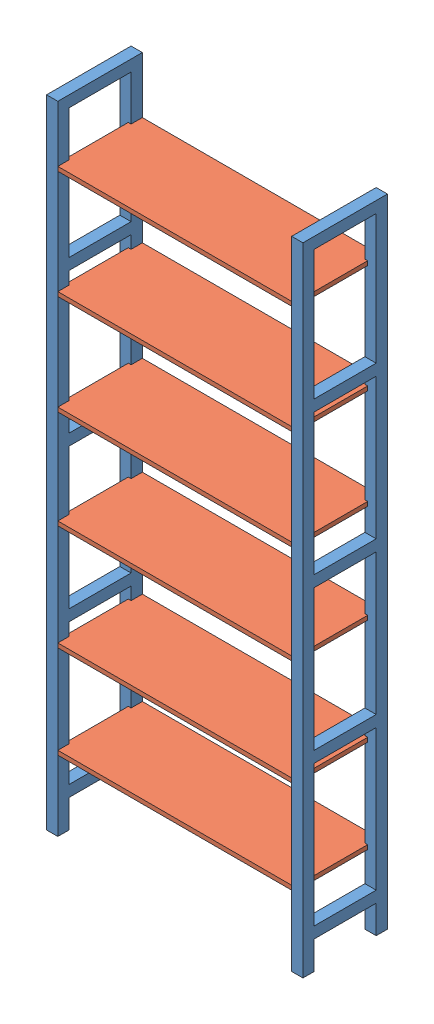
SolidWorks assembly Küchenregal, configuration Standard. Lengths in mm.
Overall size (910 2260 300).
8 component instances, 2 part files, 21 mates.
Components (placement in the parent):
- Seite-30-226-1: Seite-30-226 [Standard] at (-238.8637 -1.8239 2260) size (40 2260 300)
- Seite-30-226-2: Seite-30-226 [Standard] at (631.1363 -1.8239 2260) size (40 2260 300)
- Boden-30-83-1: Boden-30-83 [Standard] at (216.1363 913.1761 2260) size (850 15 300)
- Boden-30-83-2: Boden-30-83 [Standard] at (216.1363 528.1761 2260) size (850 15 300)
- Boden-30-83-3: Boden-30-83 [Standard] at (216.1363 173.1761 2260) size (850 15 300)
- Boden-30-83-4: Boden-30-83 [Standard] at (216.1363 -176.8239 2260) size (850 15 300)
- Boden-30-83-5: Boden-30-83 [Standard] at (216.1363 -551.8239 2260) size (850 15 300)
- Boden-30-83-6: Boden-30-83 [Standard] at (216.1363 -881.8239 2260) size (850 15 300)
Mates (geometry in assembly coordinates):
- Deckungsgleich1: coincident anti-aligned: plane of Seite-30-226-1 through (-198.8637 -1.8239 2260) normal (1 0 0); plane of Boden-30-83-1 through (-198.8637 928.1761 2370) normal (-1 0 0)
- Deckungsgleich2: coincident anti-aligned: plane of Seite-30-226-1 through (-198.8637 -1.8239 2260) normal (1 0 0); plane of Boden-30-83-2 through (-198.8637 543.1761 2370) normal (-1 0 0)
- Deckungsgleich3: coincident anti-aligned: plane of Seite-30-226-1 through (-198.8637 -1.8239 2260) normal (1 0 0); plane of Boden-30-83-3 through (-198.8637 188.1761 2370) normal (-1 0 0)
- Deckungsgleich4: coincident anti-aligned: plane of Seite-30-226-1 through (-198.8637 -1.8239 2260) normal (1 0 0); plane of Boden-30-83-4 through (-198.8637 -161.8239 2370) normal (-1 0 0)
- Deckungsgleich5: coincident: plane of Seite-30-226-1 through (-198.8637 -1.8239 2260) normal (1 0 0); plane of Boden-30-83-6 through (-198.8637 -866.8239 2370) normal (-1 0 0)
- Deckungsgleich6: coincident aligned: plane of Seite-30-226-1 through (-198.8637 1128.1761 2410) normal (0 0 1); plane of Boden-30-83-6 through (-198.8637 -866.8239 2410) normal (0 0 1)
- Deckungsgleich7: coincident: plane of Seite-30-226-1 through (-198.8637 1128.1761 2410) normal (0 0 1); plane of Boden-30-83-5 through (-198.8637 -536.8239 2410) normal (0 0 1)
- Deckungsgleich8: coincident: plane of Seite-30-226-1 through (-198.8637 -1.8239 2260) normal (1 0 0); plane of Boden-30-83-5 through (-198.8637 -536.8239 2370) normal (-1 0 0)
- Deckungsgleich9: coincident aligned: plane of Seite-30-226-1 through (-198.8637 1128.1761 2410) normal (0 0 1); plane of Boden-30-83-4 through (-198.8637 -161.8239 2410) normal (0 0 1)
- Deckungsgleich10: coincident: plane of Seite-30-226-1 through (-198.8637 1128.1761 2410) normal (0 0 1); plane of Boden-30-83-3 through (-198.8637 188.1761 2410) normal (0 0 1)
- Deckungsgleich11: coincident aligned: plane of Seite-30-226-1 through (-198.8637 1128.1761 2410) normal (0 0 1); plane of Boden-30-83-2 through (-198.8637 543.1761 2410) normal (0 0 1)
- Deckungsgleich12: coincident aligned: plane of Seite-30-226-1 through (-198.8637 1128.1761 2410) normal (0 0 1); plane of Boden-30-83-1 through (-198.8637 928.1761 2410) normal (0 0 1)
- Deckungsgleich13: coincident aligned: plane of Seite-30-226-2 through (671.1363 1128.1761 2410) normal (0 0 1); plane of Boden-30-83-1 through (-198.8637 928.1761 2410) normal (0 0 1)
- Deckungsgleich14: coincident anti-aligned: plane of Seite-30-226-2 through (631.1363 -1.8239 2260) normal (-1 0 0); plane of Boden-30-83-1 through (631.1363 928.1761 2410) normal (1 0 0)
- Deckungsgleich15: coincident aligned: plane of Seite-30-226-1 through (-198.8637 1128.1761 2410) normal (0 1 0); plane of Seite-30-226-2 through (671.1363 1128.1761 2410) normal (0 1 0)
- Abstand1: distance = 250 mm aligned: plane of Boden-30-83-6 through (216.1363 -881.8239 2260) normal (0 -1 0); plane of Seite-30-226-2 through (671.1363 -1131.8239 2410) normal (0 -1 0)
- Abstand2: distance = 315 mm: plane of Boden-30-83-5 through (216.1363 -551.8239 2260) normal (0 -1 0); plane of Boden-30-83-6 through (216.1363 -866.8239 2260) normal (0 1 0)
- Abstand3: distance = 360 mm: plane of Boden-30-83-5 through (216.1363 -536.8239 2260) normal (0 1 0); plane of Boden-30-83-4 through (216.1363 -176.8239 2260) normal (0 -1 0)
- Abstand4: distance = 335 mm: plane of Boden-30-83-3 through (216.1363 173.1761 2260) normal (0 -1 0); plane of Boden-30-83-4 through (216.1363 -161.8239 2260) normal (0 1 0)
- Abstand5: distance = 340 mm anti-aligned: plane of Boden-30-83-2 through (216.1363 528.1761 2260) normal (0 -1 0); plane of Boden-30-83-3 through (216.1363 188.1761 2260) normal (0 1 0)
- Abstand6: distance = 370 mm: plane of Boden-30-83-2 through (216.1363 543.1761 2260) normal (0 1 0); plane of Boden-30-83-1 through (216.1363 913.1761 2260) normal (0 -1 0)
